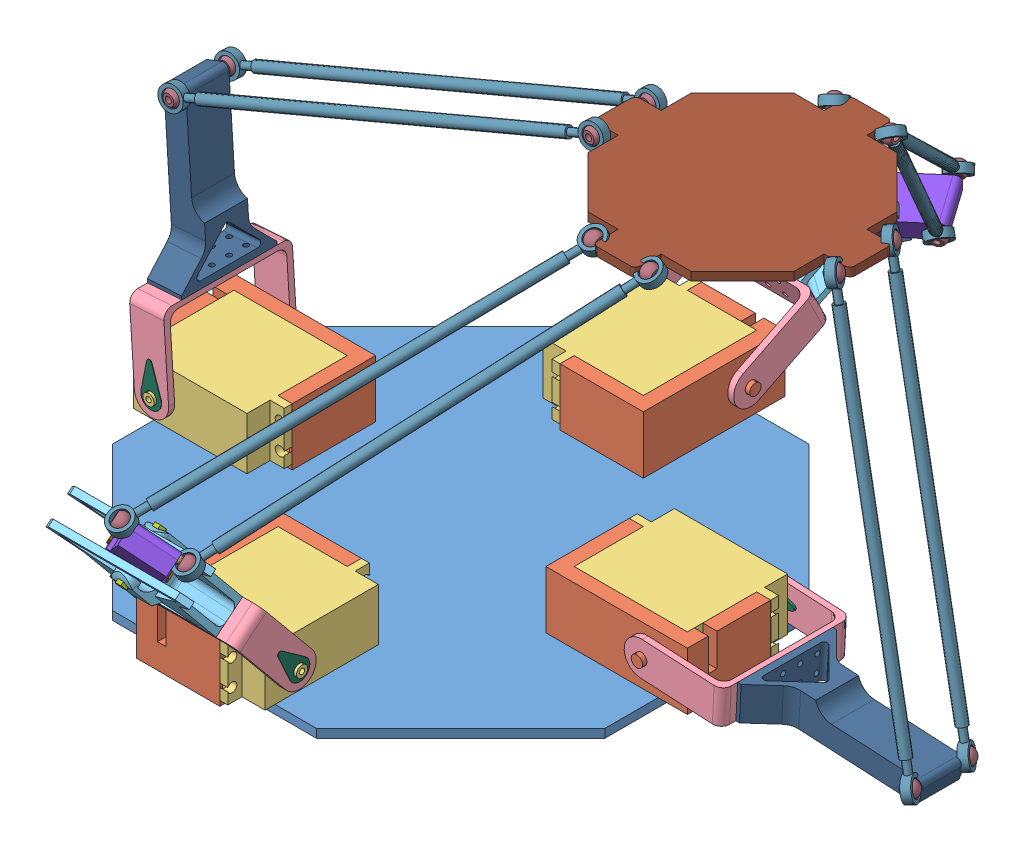
SolidWorks assembly asm, configuration 기본. Lengths in mm.
Overall size (442.58 240.3 493.2).
66 component instances, 15 part files, 155 mates.
Components (placement in the parent):
- delta_base_-1: delta_base_ [기본] at (16.2815 -22.3997 221) size (287.2 5 287.2)
- servobracket1_-1: servobracket1_ [기본] at (8418.954 -14.3997 21660.4366) x (0 0 -1) z (0 1 0) size (82.55 54.75 33.48)
- servobracket1_-2: servobracket1_ [기본] at (-21423.155 -14.3997 8623.6725) x (1 0 0) z (0 1 0) size (82.55 54.75 33.48)
- servobracket1_-3: servobracket1_ [기본] at (-8386.3909 -14.3997 -21218.4366) x (0 0 1) z (0 1 0) size (82.55 54.75 33.48)
- servobracket1_-4: servobracket1_ [기본] at (21455.7181 -14.3997 -8181.6725) x (-1 0 0) z (0 1 0) size (82.55 54.75 33.48)
- servo_drive_HV2060MG-1: servo_drive_HV2060MG [기본] at (-103.0792 0.8403 200.815) x (-1 0 0) z (0 0 1) size (82.55 30.48 64.98)
- servo_drive_HV2060MG-2: servo_drive_HV2060MG [기본] at (36.4665 0.8403 101.6393) x (0 0 -1) z (-1 0 0) size (82.55 30.48 64.98)
- servo_drive_HV2060MG-3: servo_drive_HV2060MG [기본] at (135.6423 0.8403 241.185) x (1 0 0) z (0 0 -1) size (82.55 30.48 64.98)
- servo_drive_HV2060MG-4: servo_drive_HV2060MG [기본] at (-3.9035 0.8403 340.3607) x (0 0 1) z (1 0 0) size (82.55 30.48 64.98)
- servobracket2_-1: servobracket2_ [기본] at (20.8415 37.0521 388.2427) x (1 0 0) z (0 0.637486 -0.770462) size (75 57 20)
- servobracket2_-2: servobracket2_ [기본] at (11.7215 21.7678 41.6354) x (-1 0 0) z (0 0.895399 0.445265) size (75 57 20)
- univ_link1-1: univ_link1 [기본] at (14.8415 54.2265 402.4529) x (0 -0.637486 0.770462) z (1 0 0) size (28.84 52.05 83.6)
- univ_link1-2: univ_link1 [기본] at (5.7215 31.6932 21.676) x (0 0.895399 0.445265) z (1 0 0) size (28.84 52.05 83.6)
- ball-1: ball [기본] at (20.8415 65.7873 412.0184) x (-0.801274 0.460966 0.381406) z (0 0.637486 -0.770462) size (18 14 18)
- ball-2: ball [기본] at (11.7215 38.3744 8.2405) x (0.448559 -0.397957 0.800266) z (0 0.895399 0.445265) size (18 14 18)
- univ_bolt_-1: univ_bolt_ [기본] at (20.8415 75.3495 400.4617) x (1 0 0) z (0 -0.770462 -0.637486) size (6.46 12 5.59)
- univ_bolt_-2: univ_bolt_ [기본] at (11.7215 51.8056 14.9195) x (0.5 -0.385611 0.775438) z (0.866025 0.222632 -0.447699) size (6.46 12 5.59)
- univ_bolt_-3: univ_bolt_ [기본] at (20.8415 56.2249 423.5755) x (1 0 0) z (0 0.770462 0.637486) size (6.46 12 5.59)
- univ_bolt_-4: univ_bolt_ [기본] at (11.7215 24.9436 1.5616) x (0.5 0.385611 -0.775438) z (0.866025 -0.222632 0.447699) size (6.46 12 5.59)
- univ_link2-3: univ_link2 [기본] at (25.1245 46.7363 4.9005) x (-0.448559 0.397957 -0.800266) z (0 -0.895399 -0.445265) size (28.56 68.77 12)
- univ_bolt2_-1: univ_bolt2_ [기본] at (18.455 32.4006 20.2535) x (0 0.895399 0.445265) z (-0.893753 -0.199728 0.401639) size (6.46 12 5.59)
- univ_bolt2_-2: univ_bolt2_ [기본] at (4.9982 44.3393 -3.7545) x (0 -0.895399 -0.445265) z (-0.893753 -0.199728 0.401639) size (6.46 12 5.59)
- univ_link2-4: univ_link2 [기본] at (29.8192 78.8615 415.0486) x (0.801274 -0.460966 -0.381406) z (0 -0.637486 0.770462) size (28.56 68.77 12)
- univ_bolt2_-3: univ_bolt2_ [기본] at (8.8315 72.6966 417.7352) x (0 0.637486 -0.770462) z (-0.598298 -0.617351 -0.510801) size (6.46 12 5.59)
- univ_bolt2_-4: univ_bolt2_ [기본] at (32.8697 58.8676 406.293) x (0 -0.637486 0.770462) z (-0.598298 -0.617351 -0.510801) size (6.46 12 5.59)
- servobracket2_-3: servobracket2_ [기본] at (-124.0262 47.7428 225.56) x (0 0 1) z (0.997924 0.064401 0) size (75 57 20)
- servobracket2_-4: servobracket2_ [기본] at (200.4959 -1.6594 216.44) x (0 0 -1) z (0.053185 0.998585 0) size (75 57 20)
- link1_-1: link1_ [기본] at (201.0277 8.3265 244.19) x (0 0 -1) z (-0.998585 0.053185 0) size (55.5 20 93)
- link1_-2: link1_ [기본] at (-114.0469 48.3868 197.81) x (0 0 1) z (0.064401 -0.997924 0) size (55.5 20 93)
- delta_end_-1: delta_end_ [기본] at (153.1178 211.5354 193.4515) x (-1 0 0) z (0 0 1) size (150 5 150)
- link_bridge_-1: link_bridge_ [기본] at (290.3707 -6.4461 216.4377) x (-1 0 0) z (0 1 0) size (4.5 28.5 4.5)
- bearing-1: bearing [기본] at (290.3707 -6.4461 200.0127) x (0 1 0) z (1 0 0) size (9.35 6.85 9.35)
- link_bridge_-2: link_bridge_ [기본] at (223.1178 209.0354 193.4515) x (0.013819 0.999905 0) z (0.999905 -0.013819 0) size (4.5 28.5 4.5)
- bearing-2: bearing [기본] at (223.1178 209.0354 177.0265) x (0.999983 -0.005841 0) z (-0.005841 -0.999983 0) size (9.35 6.85 9.35)
- bearing-3: bearing [기본] at (290.3707 -6.4461 232.8627) x (1 0 0) z (0 -1 0) size (9.35 6.85 9.35)
- bearing-4: bearing [기본] at (223.1178 209.0354 209.8765) x (0 -1 0) z (1 0 0) size (9.35 6.85 9.35)
- rod-1: rod [기본] at (290.3707 -6.4461 232.8627) x (0.453983 0.233419 0.859893) z (-0.296399 0.949676 -0.101306) size (13.45 6 240.35)
- rod-2: rod [기본] at (223.1178 209.0354 177.0265) x (-0.512018 -0.247546 -0.822532) z (0.296399 -0.949676 0.101306) size (13.45 6 240.35)
- link_bridge_-3: link_bridge_ [기본] at (83.1178 209.0354 193.4515) x (0.064888 0.997893 0) z (0.997893 -0.064888 0) size (4.5 28.5 4.5)
- bearing-5: bearing [기본] at (83.1178 209.0354 209.8765) x (-0.114329 0.993443 0) z (-0.993443 -0.114329 0) size (9.35 6.85 9.35)
- bearing-6: bearing [기본] at (83.1178 209.0354 177.0265) x (1 0 0) z (0 -1 0) size (9.35 6.85 9.35)
- link_bridge_-4: link_bridge_ [기본] at (-129.8224 137.5581 225.5623) x (1 0 0) z (0 -1 0) size (4.5 28.5 4.5)
- bearing-7: bearing [기본] at (-129.8224 137.5581 209.1373) x (1 0 0) z (0 -1 0) size (9.35 6.85 9.35)
- bearing-8: bearing [기본] at (-129.8224 137.5581 241.9873) x (-1 0 0) z (0 -1 0) size (9.35 6.85 9.35)
- rod-3: rod [기본] at (83.1178 209.0354 177.0265) x (-0.330419 0.938233 -0.102679) z (-0.938476 -0.315017 0.14152) size (13.45 6 240.35)
- rod-4: rod [기본] at (-129.8224 137.5581 241.9873) x (0.331072 -0.937272 0.109147) z (0.938476 0.315017 -0.14152) size (13.45 6 240.35)
- link_bridge_-5: link_bridge_ [기본] at (153.1178 209.0354 123.4515) x (0 1 0) z (0 0 1) size (4.5 28.5 4.5)
- link_bridge_-6: link_bridge_ [기본] at (64.9154 53.1941 -14.8233) x (0.246474 0.915757 0.317237) z (0.859096 -0.054945 -0.508857) size (4.5 28.5 4.5)
- bearing-9: bearing [기본] at (136.6928 209.0354 123.4515) x (0 -0.010598 -0.999944) z (0 -0.999944 0.010598) size (9.35 6.85 9.35)
- bearing-10: bearing [기본] at (169.5428 209.0354 123.4515) x (0 0.847153 0.531349) z (0 -0.531349 0.847153) size (9.35 6.85 9.35)
- bearing-11: bearing [기본] at (57.5479 59.7305 -27.9676) x (-0.246474 -0.915757 -0.317237) z (-0.859096 0.054945 0.508857) size (9.35 6.85 9.35)
- bearing-12: bearing [기본] at (72.283 46.6576 -1.6789) x (0.246474 0.915757 0.317237) z (-0.859096 0.054945 0.508857) size (9.35 6.85 9.35)
- rod-5: rod [기본] at (136.6928 209.0354 123.4515) x (-0.817318 -0.134862 0.560181) z (-0.34881 -0.658021 -0.667338) size (13.45 6 240.35)
- rod-6: rod [기본] at (72.283 46.6576 -1.6789) x (0.668324 0.159582 -0.726551) z (0.428646 0.715636 0.551478) size (13.45 6 240.35)
- link_bridge_-8: link_bridge_ [기본] at (57.013 104.3579 440.0382) x (0.549548 0.819096 0.164558) z (0.236553 -0.341457 0.909643) size (4.5 28.5 4.5)
- bearing-13: bearing [기본] at (70.174 96.7865 433.7736) x (0.587402 0.727213 0.355134) z (0.113659 -0.508598 0.853469) size (9.35 6.85 9.35)
- bearing-15: bearing [기본] at (43.8521 111.9292 446.3028) x (-0.549555 -0.819085 -0.164587) z (0.236535 -0.341483 0.909638) size (9.35 6.85 9.35)
- rod-8: rod [기본] at (70.174 96.7865 433.7736) x (-0.894848 0.159685 -0.416831) z (0.437941 0.494706 -0.750649) size (13.45 6 240.35)
- rod-9: rod [기본] at (43.8521 111.9292 446.3028) x (-0.912189 0.213317 -0.349868) z (0.40917 0.427969 -0.805868) size (13.45 6 240.35)
- servobracket3_-2: servobracket3_ [기본] at (153.5748 0.8403 177.7076) x (0.053185 0.998585 0) z (0.998585 -0.053185 0) size (12 5 24.89)
- servobracket3_-3: servobracket3_ [기본] at (54.5739 0.8403 358.2932) x (0 -0.637486 0.770462) z (0 0.770462 0.637486) size (12 5 24.89)
- servobracket3_-4: servobracket3_ [기본] at (-22.0109 0.8403 83.7068) x (0 -0.895399 -0.445265) z (0 0.445265 -0.895399) size (12 5 24.89)
- servobracket3_-5: servobracket3_ [기본] at (-121.0117 0.8403 259.2924) x (-0.997924 -0.064401 0) z (-0.064401 0.997924 0) size (12 5 24.89)
- link_bridge_-9: link_bridge_ [기본] at (153.1178 209.0354 263.4515) x (0 1 0) z (0 0 -1) size (4.5 28.5 4.5)
- bearing-17: bearing [기본] at (169.5428 209.0354 263.4515) x (0 0.970974 0.239183) z (0 0.239183 -0.970974) size (9.35 6.85 9.35)
- bearing-18: bearing [기본] at (136.6928 209.0354 263.4515) x (0 0.908606 0.417655) z (0 -0.417655 0.908606) size (9.35 6.85 9.35)
Mates (geometry in assembly coordinates):
- 동심1: concentric anti-aligned: cylinder of delta_base_-1 through (11.2815 -17.3997 82.46) axis (0 -1 0) radius 1.5; cylinder of servobracket1_-1 through (11.2815 -17.3997 82.46) axis (0 1 0) radius 1.5
- 동심2: concentric anti-aligned: cylinder of delta_base_-1 through (21.2815 -17.3997 92.46) axis (0 -1 0) radius 1.5; cylinder of servobracket1_-1 through (21.2815 -17.3997 92.46) axis (0 1 0) radius 1.5
- 일치1: coincident anti-aligned: plane of delta_base_-1 through (16.2815 -17.3997 221) normal (0 1 0); plane of servobracket1_-1 through (8418.954 -17.3997 21660.4366) normal (0 -1 0)
- 동심3: concentric anti-aligned: cylinder of delta_base_-1 through (154.8215 -17.3997 216) axis (0 -1 0) radius 1.5; cylinder of servobracket1_-2 through (154.8215 -17.3997 216) axis (0 1 0) radius 1.5
- 동심4: concentric anti-aligned: cylinder of delta_base_-1 through (144.8215 -17.3997 226) axis (0 -1 0) radius 1.5; cylinder of servobracket1_-2 through (144.8215 -17.3997 226) axis (0 1 0) radius 1.5
- 일치4: coincident anti-aligned: plane of delta_base_-1 through (16.2815 -17.3997 221) normal (0 1 0); plane of servobracket1_-2 through (-21423.155 -17.3997 8623.6725) normal (0 -1 0)
- 동심5: concentric anti-aligned: cylinder of delta_base_-1 through (21.2815 -17.3997 359.54) axis (0 -1 0) radius 1.5; cylinder of servobracket1_-3 through (21.2815 -17.3997 359.54) axis (0 1 0) radius 1.5
- 동심6: concentric anti-aligned: cylinder of delta_base_-1 through (11.2815 -17.3997 349.54) axis (0 -1 0) radius 1.5; cylinder of servobracket1_-3 through (11.2815 -17.3997 349.54) axis (0 1 0) radius 1.5
- 일치5: coincident anti-aligned: plane of delta_base_-1 through (16.2815 -17.3997 221) normal (0 1 0); plane of servobracket1_-3 through (-8386.3909 -17.3997 -21218.4366) normal (0 -1 0)
- 동심7: concentric anti-aligned: cylinder of delta_base_-1 through (-122.2585 -17.3997 226) axis (0 -1 0) radius 1.5; cylinder of servobracket1_-4 through (-122.2585 -17.3997 226) axis (0 1 0) radius 1.5
- 동심8: concentric anti-aligned: cylinder of delta_base_-1 through (-112.2585 -17.3997 216) axis (0 -1 0) radius 1.5; cylinder of servobracket1_-4 through (-112.2585 -17.3997 216) axis (0 1 0) radius 1.5
- 일치6: coincident anti-aligned: plane of delta_base_-1 through (16.2815 -17.3997 221) normal (0 1 0); plane of servobracket1_-4 through (21455.7181 -17.3997 -8181.6725) normal (0 -1 0)
- 일치7: coincident anti-aligned: plane of servobracket1_-4 through (-70.0592 16.0803 241.1804) normal (-1 0 0); plane of servo_drive_HV2060MG-1 through (-70.0592 16.0803 241.1904) normal (1 0 0)
- 일치8: coincident anti-aligned: plane of servobracket1_-4 through (-70.0592 16.0803 200.815) normal (0 0 1); plane of servo_drive_HV2060MG-1 through (-103.0792 0.8403 200.815) normal (0 0 -1)
- 일치9: coincident anti-aligned: plane of servobracket1_-4 through (21455.7181 -14.3997 -8181.6725) normal (0 1 0); plane of servo_drive_HV2060MG-1 through (-136.0992 -14.3997 241.1904) normal (0 -1 0)
- 일치10: coincident anti-aligned: plane of servobracket1_-1 through (-3.8989 16.0803 134.6593) normal (0 0 -1); plane of servo_drive_HV2060MG-2 through (-3.9089 16.0803 134.6593) normal (0 0 1)
- 일치11: coincident anti-aligned: plane of servobracket1_-1 through (36.4665 16.0803 134.6593) normal (-1 0 0); plane of servo_drive_HV2060MG-2 through (36.4665 0.8403 101.6393) normal (1 0 0)
- 일치12: coincident anti-aligned: plane of servobracket1_-1 through (8418.954 -14.3997 21660.4366) normal (0 1 0); plane of servo_drive_HV2060MG-2 through (-3.9089 -14.3997 68.6193) normal (0 -1 0)
- 일치13: coincident anti-aligned: plane of servobracket1_-2 through (102.6223 16.0803 200.8196) normal (1 0 0); plane of servo_drive_HV2060MG-3 through (102.6223 16.0803 200.8096) normal (-1 0 0)
- 일치14: coincident anti-aligned: plane of servobracket1_-2 through (102.6223 16.0803 241.185) normal (0 0 -1); plane of servo_drive_HV2060MG-3 through (135.6423 0.8403 241.185) normal (0 0 1)
- 일치15: coincident anti-aligned: plane of servobracket1_-2 through (-21423.155 -14.3997 8623.6725) normal (0 1 0); plane of servo_drive_HV2060MG-3 through (168.6623 -14.3997 200.8096) normal (0 -1 0)
- 일치16: coincident anti-aligned: plane of servobracket1_-3 through (36.4619 16.0803 307.3407) normal (0 0 1); plane of servo_drive_HV2060MG-4 through (36.4719 16.0803 307.3407) normal (0 0 -1)
- 일치17: coincident anti-aligned: plane of servobracket1_-3 through (-3.9035 16.0803 307.3407) normal (1 0 0); plane of servo_drive_HV2060MG-4 through (-3.9035 0.8403 340.3607) normal (-1 0 0)
- 일치18: coincident anti-aligned: plane of servobracket1_-3 through (-8386.3909 -14.3997 -21218.4366) normal (0 1 0); plane of servo_drive_HV2060MG-4 through (36.4719 -14.3997 373.3807) normal (0 -1 0)
- 동심12: concentric aligned: circle of servobracket1_-3; cylinder of servobracket2_-1 through (-12.1585 0.8403 358.2809) axis (-1 0 0) radius 3.3
- 일치19: coincident anti-aligned: plane of servobracket1_-3 through (-12.1585 16.0803 381.6357) normal (-1 0 0); plane of servobracket2_-1 through (-12.1585 -13.2391 359.6106) normal (1 0 0)
- 동심13: concentric aligned: circle of servobracket1_-1; cylinder of servobracket2_-2 through (44.7215 0.8403 83.7191) axis (1 0 0) radius 3.3
- 일치20: coincident anti-aligned: plane of servobracket1_-1 through (44.7215 16.0803 60.3643) normal (1 0 0); plane of servobracket2_-2 through (44.7215 -12.5663 88.2205) normal (-1 0 0)
- 동심14: concentric anti-aligned: cylinder of servobracket2_-1 through (15.8415 32.3237 390.82) axis (0 0.770462 0.637486) radius 1.5; cylinder of univ_link1-1 through (15.8415 36.176 394.0075) axis (0 -0.770462 -0.637486) radius 1.5
- 동심15: concentric anti-aligned: cylinder of servobracket2_-1 through (25.8415 38.6986 383.1154) axis (0 0.770462 0.637486) radius 1.5; cylinder of univ_link1-1 through (25.8415 42.5509 386.3029) axis (0 -0.770462 -0.637486) radius 1.5
- 일치22: coincident anti-aligned: plane of servobracket2_-1 through (20.8415 37.0521 388.2427) normal (0 0.770462 0.637486); plane of univ_link1-1 through (-6.9085 30.6772 395.9473) normal (0 -0.770462 -0.637486)
- 동심16: concentric anti-aligned: cylinder of servobracket2_-2 through (6.7215 25.3543 45.6525) axis (0 0.445265 -0.895399) radius 1.5; cylinder of univ_link1-2 through (6.7215 27.5806 41.1755) axis (0 -0.445265 0.895399) radius 1.5
- 동심17: concentric anti-aligned: cylinder of servobracket2_-2 through (16.7215 16.4003 41.1998) axis (0 0.445265 -0.895399) radius 1.5; cylinder of univ_link1-2 through (16.7215 18.6266 36.7228) axis (0 -0.445265 0.895399) radius 1.5
- 일치23: coincident anti-aligned: plane of servobracket2_-2 through (11.7215 21.7678 41.6354) normal (0 0.445265 -0.895399); plane of univ_link1-2 through (-16.0285 30.7218 46.088) normal (0 -0.445265 0.895399)
- 일치24: coincident anti-aligned: circle of univ_link1-1; circle of ball-1
- 일치26: coincident anti-aligned: plane of univ_link1-1 through (22.4565 71.9193 400.2194) normal (0 0.770462 0.637486); plane of univ_bolt_-1 through (19.2265 71.9193 400.2194) normal (0 -0.770462 -0.637486)
- 동심18: concentric aligned: cylinder of ball-1 through (20.8415 61.3249 417.4117) axis (0 0.637486 -0.770462) radius 1.55; cylinder of univ_bolt_-1 through (20.8415 67.6996 409.7072) axis (0 0.637486 -0.770462) radius 1.55
- 일치27: coincident anti-aligned: plane of univ_link1-1 through (14.8415 62.5137 392.4371) normal (0 0.637486 -0.770462); plane of univ_bolt_-1 through (20.8415 74.0745 402.0026) normal (0 -0.637486 0.770462)
- 일치28: coincident anti-aligned: plane of univ_link1-2 through (10.1065 48.7693 16.5337) normal (0 0.445265 -0.895399); plane of univ_bolt_-2 through (13.3365 48.7693 16.5337) normal (0 -0.445265 0.895399)
- 동심19: concentric aligned: cylinder of ball-2 through (11.7215 32.1066 5.1236) axis (0 0.895399 0.445265) radius 1.55; cylinder of univ_bolt_-2 through (11.7215 41.0608 9.5764) axis (0 0.895399 0.445265) radius 1.55
- 일치29: coincident anti-aligned: plane of univ_link1-2 through (5.7215 43.3336 27.4645) normal (0 0.895399 0.445265); plane of univ_bolt_-2 through (11.7215 50.0148 14.029) normal (0 -0.895399 -0.445265)
- 동심20: concentric anti-aligned: cylinder of ball-1 through (20.8415 61.3249 417.4117) axis (0 0.637486 -0.770462) radius 1.55; cylinder of univ_bolt_-3 through (20.8415 63.8747 414.33) axis (0 -0.637486 0.770462) radius 1.55
- 일치30: coincident anti-aligned: plane of univ_link1-1 through (19.2265 55.3447 420.2514) normal (0 0.770462 0.637486); plane of univ_bolt_-3 through (22.4565 55.3447 420.2514) normal (0 -0.770462 -0.637486)
- 일치31: coincident anti-aligned: plane of univ_link1-1 through (14.8415 45.9391 412.4691) normal (0 -0.637486 0.770462); plane of univ_bolt_-3 through (20.8415 57.4999 422.0346) normal (0 0.637486 -0.770462)
- 일치32: coincident anti-aligned: plane of univ_link1-2 through (13.3365 25.4889 4.9568) normal (0 0.445265 -0.895399); plane of univ_bolt_-4 through (10.1065 25.4889 4.9568) normal (0 -0.445265 0.895399)
- 동심21: concentric anti-aligned: cylinder of ball-2 through (11.7215 32.1066 5.1236) axis (0 0.895399 0.445265) radius 1.55; cylinder of univ_bolt_-4 through (11.7215 35.6884 6.9048) axis (0 -0.895399 -0.445265) radius 1.55
- 일치33: coincident anti-aligned: plane of univ_link1-2 through (5.7215 20.0532 15.8876) normal (0 -0.895399 -0.445265); plane of univ_bolt_-4 through (11.7215 26.7344 2.4521) normal (0 0.895399 0.445265)
- 일치35: coincident aligned: plane of ball-2 through (9.0251 40.9125 -0.2323) normal (0 0.895399 0.445265); plane of univ_link2-3 through (19.5331 31.5872 18.5203) normal (0 0.895399 0.445265)
- 일치37: coincident anti-aligned: plane of univ_link2-3 through (20.0579 39.1276 20.2011) normal (-0.893753 -0.199728 0.401639); plane of univ_bolt2_-1 through (20.0579 35.2013 18.2486) normal (0.893753 0.199728 -0.401639)
- 일치38: coincident anti-aligned: plane of ball-2 through (9.0251 40.9125 -0.2323) normal (0 0.895399 0.445265); plane of univ_bolt2_-1 through (14.4129 36.1326 9.38) normal (0 -0.895399 -0.445265)
- 일치39: coincident anti-aligned: plane of ball-2 through (6.3439 42.9996 2.3084) normal (0.893753 0.199728 -0.401639); plane of univ_bolt2_-1 through (11.7316 35.5334 10.5849) normal (-0.893753 -0.199728 0.401639)
- 일치40: coincident anti-aligned: plane of univ_link2-3 through (30.9556 41.5629 15.3038) normal (0.448559 -0.397957 0.800266); plane of univ_bolt2_-1 through (17.5579 33.1965 18.653) normal (-0.448559 0.397957 -0.800266)
- 일치126: coincident aligned: circle of univ_link1-2; circle of ball-2
- 일치44: coincident anti-aligned: plane of univ_link2-3 through (8.3954 45.5496 -2.5576) normal (-0.893753 -0.199728 0.401639); plane of univ_bolt2_-2 through (8.3954 42.656 -3.9965) normal (0.893753 0.199728 -0.401639)
- 일치45: coincident anti-aligned: plane of ball-2 through (9.0251 43.5987 1.1035) normal (0 -0.895399 -0.445265); plane of univ_bolt2_-2 through (11.7216 41.2065 5.9142) normal (0 0.895399 0.445265)
- 일치46: coincident anti-aligned: plane of ball-2 through (6.3439 42.9996 2.3084) normal (0.893753 0.199728 -0.401639); plane of univ_bolt2_-2 through (9.0403 40.6073 7.1191) normal (-0.893753 -0.199728 0.401639)
- 일치47: coincident anti-aligned: plane of univ_link2-3 through (19.2931 51.9098 -5.5031) normal (-0.448559 0.397957 -0.800266); plane of univ_bolt2_-2 through (5.8953 43.5434 -2.1539) normal (0.448559 -0.397957 0.800266)
- 일치49: coincident aligned: plane of ball-1 through (28.9504 61.6084 410.5077) normal (0 0.637486 -0.770462); plane of univ_link2-4 through (10.1918 72.3975 419.4346) normal (0 0.637486 -0.770462)
- 일치50: coincident anti-aligned: plane of univ_link2-4 through (12.1076 77.3265 413.7785) normal (-0.598298 -0.617351 -0.510801); plane of univ_bolt2_-3 through (12.1076 74.5311 417.157) normal (0.598298 0.617351 0.510801)
- 일치51: coincident anti-aligned: plane of ball-1 through (28.9504 61.6084 410.5077) normal (0 0.637486 -0.770462); plane of univ_bolt2_-3 through (19.3442 67.1348 415.0802) normal (0 -0.637486 0.770462)
- 일치52: coincident anti-aligned: plane of ball-1 through (27.1556 61.6688 406.6639) normal (0.598298 0.617351 0.510801); plane of univ_bolt2_-3 through (17.5493 65.2827 413.5478) normal (-0.598298 -0.617351 -0.510801)
- 일치53: coincident anti-aligned: plane of univ_link2-4 through (19.4028 84.8539 420.0068) normal (-0.801274 0.460966 0.381406); plane of univ_bolt2_-3 through (10.434 71.7747 416.9724) normal (0.801274 -0.460966 -0.381406)
- 일치54: coincident anti-aligned: plane of univ_link2-4 through (32.9407 62.547 407.2392) normal (-0.598298 -0.617351 -0.510801); plane of univ_bolt2_-4 through (32.9407 60.4869 409.729) normal (0.598298 0.617351 0.510801)
- 일치55: coincident anti-aligned: plane of ball-1 through (28.9504 63.5209 408.1963) normal (0 -0.637486 0.770462); plane of univ_bolt2_-4 through (24.1518 66.2815 410.4804) normal (0 0.637486 -0.770462)
- 일치56: coincident anti-aligned: plane of ball-1 through (27.1556 61.6688 406.6639) normal (0.598298 0.617351 0.510801); plane of univ_bolt2_-4 through (22.357 64.4294 408.948) normal (-0.598298 -0.617351 -0.510801)
- 일치57: coincident anti-aligned: plane of univ_link2-4 through (40.2359 72.8688 410.0902) normal (0.801274 -0.460966 -0.381406); plane of univ_bolt2_-4 through (31.2671 59.7896 407.0558) normal (-0.801274 0.460966 0.381406)
- 동심22: concentric aligned: circle of servobracket1_-4; cylinder of servobracket2_-3 through (-120.9993 0.8403 192.56) axis (0 0 -1) radius 3.3
- 일치58: coincident anti-aligned: plane of servobracket1_-4 through (-144.3542 16.0803 192.56) normal (0 0 -1); plane of servobracket2_-3 through (-130.3346 -9.7829 192.56) normal (0 0 1)
- 동심23: concentric aligned: circle of servobracket1_-2; cylinder of servobracket2_-4 through (153.5624 0.8403 249.44) axis (0 0 1) radius 3.3
- 일치59: coincident anti-aligned: plane of servobracket1_-2 through (176.9173 16.0803 249.44) normal (0 0 1); plane of servobracket2_-4 through (143.0447 -8.6136 249.44) normal (0 0 -1)
- 동심24: concentric anti-aligned: cylinder of servobracket2_-4 through (198.2328 -6.5459 221.44) axis (0.998585 -0.053185 0) radius 1.5; cylinder of link1_-1 through (205.2229 -6.9182 221.44) axis (-0.998585 0.053185 0) radius 1.5
- 동심25: concentric anti-aligned: cylinder of servobracket2_-4 through (198.7647 3.4399 211.44) axis (0.998585 -0.053185 0) radius 1.5; cylinder of link1_-1 through (205.7547 3.0676 211.44) axis (-0.998585 0.053185 0) radius 1.5
- 일치60: coincident anti-aligned: plane of servobracket2_-4 through (200.4959 -1.6594 216.44) normal (0.998585 -0.053185 0); plane of link1_-1 through (199.964 -11.6452 188.69) normal (-0.998585 0.053185 0)
- 동심26: concentric anti-aligned: cylinder of servobracket2_-3 through (-128.887 45.4249 230.56) axis (-0.064401 0.997924 0) radius 1.5; cylinder of link1_-2 through (-129.3378 52.4104 230.56) axis (0.064401 -0.997924 0) radius 1.5
- 동심27: concentric anti-aligned: cylinder of servobracket2_-3 through (-118.9078 46.0689 220.56) axis (-0.064401 0.997924 0) radius 1.5; cylinder of link1_-2 through (-119.3586 53.0544 220.56) axis (0.064401 -0.997924 0) radius 1.5
- 일치61: coincident anti-aligned: plane of servobracket2_-3 through (-124.0262 47.7428 225.56) normal (-0.064401 0.997924 0); plane of link1_-2 through (-134.0054 47.0988 253.31) normal (0.064401 -0.997924 0)
- 동심29: concentric anti-aligned: cylinder of link1_-1 through (290.3707 -6.4461 188.69) axis (0 0 1) radius 2.15; cylinder of link_bridge_-1 through (290.3707 -6.4461 228.9377) axis (0 0 -1) radius 2
- 일치66: coincident anti-aligned: plane of link1_-1 through (289.8367 -16.4319 228.9377) normal (0 0 1); plane of link_bridge_-1 through (290.3707 -6.4461 228.9377) normal (0 0 -1)
- 일치68: coincident anti-aligned: plane of link_bridge_-1 through (290.3707 -6.4461 203.4377) normal (0 0 -1); plane of bearing-1 through (290.3707 -6.4461 203.4377) normal (0 0 1)
- 동심30: concentric aligned: cylinder of link_bridge_-1 through (290.3707 -6.4461 202.1877) axis (0 0 1) radius 1.775; cylinder of bearing-1 through (290.3707 -6.4461 196.5877) axis (0 0 1) radius 1.775
- 동심31: concentric anti-aligned: cylinder of delta_end_-1 through (223.1178 209.0354 118.4515) axis (0 0 1) radius 2; cylinder of link_bridge_-2 through (223.1178 209.0354 205.9515) axis (0 0 -1) radius 2
- 일치70: coincident anti-aligned: plane of delta_end_-1 through (153.1178 206.5354 205.9515) normal (0 0 1); plane of link_bridge_-2 through (223.1178 209.0354 205.9515) normal (0 0 -1)
- 동심32: concentric aligned: cylinder of link_bridge_-2 through (223.1178 209.0354 179.2015) axis (0 0 1) radius 1.775; cylinder of bearing-2 through (223.1178 209.0354 173.6015) axis (0 0 1) radius 1.775
- 일치71: coincident anti-aligned: plane of link_bridge_-2 through (223.1178 209.0354 180.4515) normal (0 0 -1); plane of bearing-2 through (223.1178 209.0354 180.4515) normal (0 0 1)
- 동심35: concentric anti-aligned: cylinder of link_bridge_-1 through (290.3707 -6.4461 230.6877) axis (0 0 -1) radius 1.775; cylinder of bearing-3 through (290.3707 -6.4461 229.4377) axis (0 0 1) radius 1.775
- 일치76: coincident anti-aligned: plane of link_bridge_-1 through (290.3707 -6.4461 229.4377) normal (0 0 1); plane of bearing-3 through (290.3707 -6.4461 229.4377) normal (0 0 -1)
- 일치78: coincident anti-aligned: plane of link_bridge_-2 through (223.1178 209.0354 206.4515) normal (0 0 1); plane of bearing-4 through (223.1178 209.0354 206.4515) normal (0 0 -1)
- 동심36: concentric aligned: cylinder of link_bridge_-2 through (223.1178 209.0354 207.7015) axis (0 0 -1) radius 1.775; cylinder of bearing-4 through (223.1178 209.0354 213.3015) axis (0 0 -1) radius 1.775
- 일치79: coincident: sphere of bearing-3; circle of rod-1
- 일치80: coincident: sphere of bearing-4; circle of rod-1
- 일치81: coincident: sphere of bearing-1; circle of rod-2
- 일치82: coincident: sphere of bearing-2; circle of rod-2
- 동심37: concentric anti-aligned: cylinder of delta_end_-1 through (83.1178 209.0354 118.4515) axis (0 0 1) radius 2; cylinder of link_bridge_-3 through (83.1178 209.0354 205.9515) axis (0 0 -1) radius 2
- 일치83: coincident anti-aligned: plane of delta_end_-1 through (153.1178 206.5354 180.9515) normal (0 0 -1); plane of link_bridge_-3 through (83.1178 209.0354 180.9515) normal (0 0 1)
- 동심38: concentric aligned: cylinder of link_bridge_-3 through (83.1178 209.0354 207.7015) axis (0 0 -1) radius 1.775; cylinder of bearing-5 through (83.1178 209.0354 213.3015) axis (0 0 -1) radius 1.775
- 일치84: coincident anti-aligned: plane of link_bridge_-3 through (83.1178 209.0354 206.4515) normal (0 0 1); plane of bearing-5 through (83.1178 209.0354 206.4515) normal (0 0 -1)
- 동심39: concentric aligned: cylinder of link_bridge_-3 through (83.1178 209.0354 179.2015) axis (0 0 1) radius 1.775; cylinder of bearing-6 through (83.1178 209.0354 173.6015) axis (0 0 1) radius 1.775
- 일치85: coincident anti-aligned: plane of link_bridge_-3 through (83.1178 209.0354 180.4515) normal (0 0 -1); plane of bearing-6 through (83.1178 209.0354 180.4515) normal (0 0 1)
- 동심40: concentric aligned: cylinder of link1_-2 through (-129.8224 137.5581 253.31) axis (0 0 -1) radius 2.15; cylinder of link_bridge_-4 through (-129.8224 137.5581 238.0623) axis (0 0 -1) radius 2
- 일치86: coincident anti-aligned: plane of link1_-2 through (-139.8015 136.9119 213.0623) normal (0 0 -1); plane of link_bridge_-4 through (-129.8224 137.5581 213.0623) normal (0 0 1)
- 동심41: concentric aligned: cylinder of link_bridge_-4 through (-129.8224 137.5581 211.3123) axis (0 0 1) radius 1.775; cylinder of bearing-7 through (-129.8224 137.5581 205.7123) axis (0 0 1) radius 1.775
- 일치87: coincident anti-aligned: plane of link_bridge_-4 through (-129.8224 137.5581 212.5623) normal (0 0 -1); plane of bearing-7 through (-129.8224 137.5581 212.5623) normal (0 0 1)
- 동심42: concentric aligned: cylinder of link_bridge_-4 through (-129.8224 137.5581 239.8123) axis (0 0 -1) radius 1.775; cylinder of bearing-8 through (-129.8224 137.5581 245.4123) axis (0 0 -1) radius 1.775
- 일치88: coincident anti-aligned: plane of link_bridge_-4 through (-129.8224 137.5581 238.5623) normal (0 0 1); plane of bearing-8 through (-129.8224 137.5581 238.5623) normal (0 0 -1)
- 일치89: coincident: sphere of bearing-7; circle of rod-3
- 일치91: coincident: sphere of bearing-6; circle of rod-3
- 일치93: coincident: sphere of bearing-5; circle of rod-4
- 일치95: coincident: sphere of bearing-8; circle of rod-4
- 동심43: concentric aligned: cylinder of delta_end_-1 through (78.1178 209.0354 123.4515) axis (1 0 0) radius 2; cylinder of link_bridge_-5 through (140.6178 209.0354 123.4515) axis (1 0 0) radius 2
- 일치96: coincident anti-aligned: plane of delta_end_-1 through (165.6178 206.5354 193.4515) normal (1 0 0); plane of link_bridge_-5 through (165.6178 209.0354 123.4515) normal (-1 0 0)
- 동심44: concentric aligned: cylinder of univ_link2-3 through (71.6105 47.2543 -2.8788) axis (-0.448559 0.397957 -0.800266) radius 2; cylinder of link_bridge_-6 through (70.5224 48.2196 -4.82) axis (-0.448559 0.397957 -0.800266) radius 2
- 일치97: coincident anti-aligned: plane of univ_link2-3 through (70.5224 40.161 -8.8273) normal (0.448559 -0.397957 0.800266); plane of link_bridge_-6 through (70.5224 48.2196 -4.82) normal (-0.448559 0.397957 -0.800266)
- 동심45: concentric aligned: cylinder of link_bridge_-5 through (138.8678 209.0354 123.4515) axis (1 0 0) radius 1.775; cylinder of bearing-9 through (133.2678 209.0354 123.4515) axis (1 0 0) radius 1.775
- 일치98: coincident anti-aligned: plane of link_bridge_-5 through (140.1178 209.0354 123.4515) normal (-1 0 0); plane of bearing-9 through (140.1178 209.0354 123.4515) normal (1 0 0)
- 동심46: concentric aligned: cylinder of link_bridge_-5 through (167.3678 209.0354 123.4515) axis (-1 0 0) radius 1.775; cylinder of bearing-10 through (172.9678 209.0354 123.4515) axis (-1 0 0) radius 1.775
- 일치99: coincident anti-aligned: plane of link_bridge_-5 through (166.1178 209.0354 123.4515) normal (1 0 0); plane of bearing-10 through (166.1178 209.0354 123.4515) normal (-1 0 0)
- 동심47: concentric aligned: cylinder of link_bridge_-6 through (58.5235 58.865 -26.2271) axis (0.448559 -0.397957 0.800266) radius 1.775; cylinder of bearing-11 through (56.0115 61.0935 -30.7086) axis (0.448559 -0.397957 0.800266) radius 1.775
- 일치100: coincident anti-aligned: plane of link_bridge_-6 through (59.0842 58.3675 -25.2267) normal (-0.448559 0.397957 -0.800266); plane of bearing-11 through (59.0842 58.3675 -25.2267) normal (0.448559 -0.397957 0.800266)
- 동심48: concentric aligned: cylinder of link_bridge_-6 through (71.3074 47.5232 -3.4195) axis (-0.448559 0.397957 -0.800266) radius 1.775; cylinder of bearing-12 through (73.8193 45.2946 1.062) axis (-0.448559 0.397957 -0.800266) radius 1.775
- 일치101: coincident anti-aligned: plane of link_bridge_-6 through (70.7467 48.0206 -4.4198) normal (0.448559 -0.397957 0.800266); plane of bearing-12 through (70.7467 48.0206 -4.4198) normal (-0.448559 0.397957 -0.800266)
- 일치102: coincident: sphere of bearing-11; circle of rod-5
- 일치103: coincident: sphere of bearing-9; circle of rod-5
- 일치104: coincident: sphere of bearing-12; circle of rod-6
- 일치107: coincident: sphere of bearing-10; circle of rod-6
- 동심50: concentric aligned: cylinder of univ_link2-4 through (45.0535 111.2381 445.731) axis (0.801274 -0.460966 -0.381406) radius 2; cylinder of link_bridge_-8 through (46.9971 110.1199 444.8058) axis (0.801274 -0.460966 -0.381406) radius 2
- 일치111: coincident anti-aligned: plane of univ_link2-4 through (46.9971 104.3826 451.7399) normal (-0.801274 0.460966 0.381406); plane of link_bridge_-8 through (46.9971 110.1199 444.8058) normal (0.801274 -0.460966 -0.381406)
- 동심51: concentric aligned: cylinder of link_bridge_-8 through (68.4312 97.7891 434.6032) axis (-0.801274 0.460966 0.381406) radius 1.775; cylinder of bearing-13 through (72.9183 95.2077 432.4673) axis (-0.801274 0.460966 0.381406) radius 1.775
- 일치112: coincident anti-aligned: plane of link_bridge_-8 through (67.4296 98.3653 435.0799) normal (0.801274 -0.460966 -0.381406); plane of bearing-13 through (67.4296 98.3653 435.0799) normal (-0.801274 0.460966 0.381406)
- 동심53: concentric aligned: cylinder of link_bridge_-8 through (45.5949 110.9266 445.4732) axis (0.801274 -0.460966 -0.381406) radius 1.775; cylinder of bearing-15 through (41.1078 113.508 447.6091) axis (0.801274 -0.460966 -0.381406) radius 1.775
- 일치116: coincident anti-aligned: plane of link_bridge_-8 through (46.5965 110.3504 444.9965) normal (-0.801274 0.460966 0.381406); plane of bearing-15 through (46.5965 110.3504 444.9965) normal (0.801274 -0.460966 -0.381406)
- 일치117: coincident: sphere of bearing-13; circle of rod-8
- 일치120: coincident: sphere of bearing-15; circle of rod-9
- 탄젠트2: tangent: circle of ball-1; plane of univ_link2-4 through (11.2575 63.9849 418.3146) normal (0.801274 -0.460966 -0.381406)
- 동심56: concentric anti-aligned: cylinder of servo_drive_HV2060MG-3 through (153.5748 0.8403 176.2076) axis (0 0 1) radius 3.302; cylinder of servobracket3_-2 through (153.5748 0.8403 182.7076) axis (0 0 -1) radius 3.3
- 일치123: coincident anti-aligned: plane of servo_drive_HV2060MG-3 through (135.6423 0.8403 182.7076) normal (0 0 -1); plane of servobracket3_-2 through (153.5748 0.8403 182.7076) normal (0 0 1)
- 평행1: parallel anti-aligned: plane of servobracket2_-4 through (199.2194 4.3715 181.44) normal (-0.20708 0.978324 0); plane of servobracket3_-2 through (154.8173 -5.0296 182.7076) normal (0.20708 -0.978324 0)
- 동심57: concentric aligned: cylinder of servo_drive_HV2060MG-4 through (61.0739 0.8403 358.2932) axis (-1 0 0) radius 3.302; cylinder of servobracket3_-3 through (59.5739 0.8403 358.2932) axis (-1 0 0) radius 3.3
- 일치127: coincident anti-aligned: plane of servo_drive_HV2060MG-4 through (54.5739 0.8403 340.3607) normal (1 0 0); plane of servobracket3_-3 through (54.5739 0.8403 358.2932) normal (-1 0 0)
- 평행2: parallel anti-aligned: plane of servobracket2_-1 through (55.8415 39.6187 382.6379) normal (0 0.416354 -0.909203); plane of servobracket3_-3 through (59.5739 -1.6578 363.7485) normal (0 -0.416354 0.909203)
- 동심58: concentric aligned: cylinder of servo_drive_HV2060MG-2 through (-28.5109 0.8403 83.7068) axis (1 0 0) radius 3.302; cylinder of servobracket3_-4 through (-27.0109 0.8403 83.7068) axis (1 0 0) radius 3.3
- 일치129: coincident anti-aligned: plane of servo_drive_HV2060MG-2 through (-22.0109 0.8403 101.6393) normal (-1 0 0); plane of servobracket3_-4 through (-22.0109 0.8403 83.7068) normal (1 0 0)
- 평행3: parallel anti-aligned: plane of servobracket2_-2 through (-23.2785 26.389 45.7153) normal (0 0.749646 0.661839); plane of servobracket3_-4 through (-27.0109 -3.6575 79.7357) normal (0 -0.749646 -0.661839)
- 동심59: concentric aligned: cylinder of servo_drive_HV2060MG-1 through (-121.0117 0.8403 265.7924) axis (0 0 -1) radius 3.302; cylinder of servobracket3_-5 through (-121.0117 0.8403 264.2924) axis (0 0 -1) radius 3.3
- 일치131: coincident anti-aligned: plane of servo_drive_HV2060MG-1 through (-103.0792 0.8403 259.2924) normal (0 0 1); plane of servobracket3_-5 through (-121.0117 0.8403 259.2924) normal (0 0 -1)
- 평행4: parallel anti-aligned: plane of servobracket2_-3 through (-117.9813 46.5341 260.56) normal (0.980589 -0.196076 0); plane of servobracket3_-5 through (-126.8952 2.0168 264.2924) normal (-0.980589 0.196076 0)
- 동심60: concentric anti-aligned: cylinder of delta_end_-1 through (78.1178 209.0354 263.4515) axis (1 0 0) radius 2; cylinder of link_bridge_-9 through (165.6178 209.0354 263.4515) axis (-1 0 0) radius 2
- 일치132: coincident anti-aligned: plane of delta_end_-1 through (140.6178 206.5354 193.4515) normal (-1 0 0); plane of link_bridge_-9 through (140.6178 209.0354 263.4515) normal (1 0 0)
- 동심61: concentric anti-aligned: cylinder of link_bridge_-9 through (167.3678 209.0354 263.4515) axis (-1 0 0) radius 1.775; cylinder of bearing-17 through (166.1178 209.0354 263.4515) axis (1 0 0) radius 1.775
- 일치133: coincident anti-aligned: plane of link_bridge_-9 through (166.1178 209.0354 263.4515) normal (1 0 0); plane of bearing-17 through (166.1178 209.0354 263.4515) normal (-1 0 0)
- 동심62: concentric anti-aligned: cylinder of link_bridge_-9 through (138.8678 209.0354 263.4515) axis (1 0 0) radius 1.775; cylinder of bearing-18 through (140.1178 209.0354 263.4515) axis (-1 0 0) radius 1.775
- 일치134: coincident anti-aligned: plane of link_bridge_-9 through (140.1178 209.0354 263.4515) normal (-1 0 0); plane of bearing-18 through (140.1178 209.0354 263.4515) normal (1 0 0)
- 일치136: coincident: circle of rod-8; sphere of bearing-17
- 일치137: coincident: circle of rod-9; sphere of bearing-18
- 탄젠트5: tangent: circle of ball-2; plane of univ_link2-3 through (4.3274 35.958 -0.3753) normal (0.448559 -0.397957 0.800266)
- 평행5: parallel anti-aligned: plane of delta_base_-1 through (16.2815 -17.3997 221) normal (0 1 0); plane of delta_end_-1 through (153.1178 206.5354 193.4515) normal (0 -1 0)
